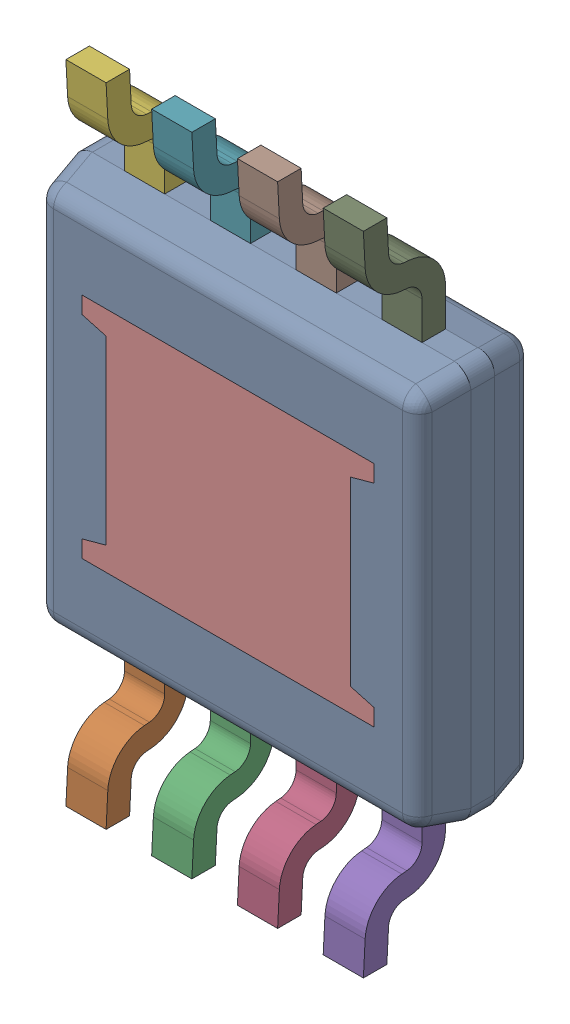
SolidWorks assembly U600_1PCB, configuration Default. Lengths in mm.
Overall size (3 4.9 0.97).
11 component instances, 3 part files, 0 mates.
Components (placement in the parent):
- MUY08A_ASM-1: MUY08A_ASM [Default] at (102.8036 110.5501 -2.2638) x (-1 0 0) z (0 -1 0) size (3 0.97 4.9)
  - BODY_MUY08A-1: BODY_MUY08A [Default] at origin size (3 0.86 3)
  - LEAD_MUY08A-1: LEAD_MUY08A [Default] at (0.9754 -0.3683 1.9177) size (0.31 0.62 0.95)
  - LEAD_MUY08A-2: LEAD_MUY08A [Default] at (0.3251 -0.3683 1.9177) size (0.31 0.62 0.95)
  - LEAD_MUY08A-3: LEAD_MUY08A [Default] at (-0.3251 -0.3683 1.9177) size (0.31 0.62 0.95)
  - LEAD_MUY08A-4: LEAD_MUY08A [Default] at (-0.9754 -0.3683 1.9177) size (0.31 0.62 0.95)
  - LEAD_MUY08A-5: LEAD_MUY08A [Default] at (0.9754 -0.3683 -1.9177) x (-1 0 0) z (0 0 -1) size (0.31 0.62 0.95)
  - LEAD_MUY08A-6: LEAD_MUY08A [Default] at (0.3251 -0.3683 -1.9177) x (-1 0 0) z (0 0 -1) size (0.31 0.62 0.95)
  - LEAD_MUY08A-7: LEAD_MUY08A [Default] at (-0.3251 -0.3683 -1.9177) x (-1 0 0) z (0 0 -1) size (0.31 0.62 0.95)
  - LEAD_MUY08A-8: LEAD_MUY08A [Default] at (-0.9754 -0.3683 -1.9177) x (-1 0 0) z (0 0 -1) size (0.31 0.62 0.95)
  - EXP_PAD_MUY08A-1: EXP_PAD_MUY08A [Default] at (0 -0.3429 0) size (2.21 0.3 1.73)
